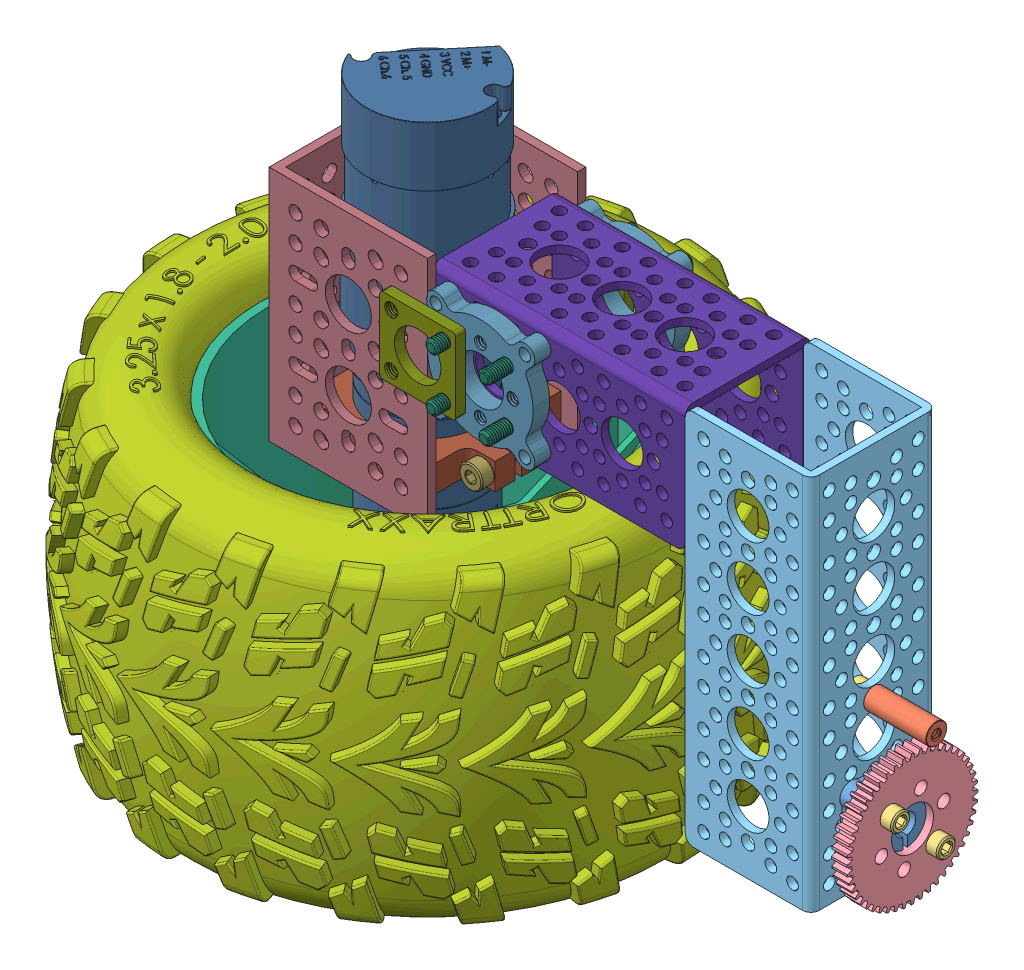
SolidWorks assembly Corner Wheel Assembly, configuration Default. Lengths in mm.
Overall size (237.64 178.61 166.05).
40 component instances, 18 part files, 13 mates.
Components (placement in the parent):
- steering-fixture-top^Corner Wheel Assembly-1: steering-fixture-top^Corner Wheel Assembly [Default] at (135.25 0 0) size (57.26 119.56 48.62) (virtual)
  - 0.25 Face Tapped Clamping Hub-1: 0.25 Face Tapped Clamping Hub [Default] at (9.525 0 0) x (0 0 -1) z (0 1 0) size (20.57 9.63 26.29)
  - 6_32 standoff-1: 6_32 standoff [Default] at (0 28.575 0) x (0 -0.906043 -0.423186) z (0 -0.423186 0.906043) size (6.34 19.26 6.34)
  - 6-32_SHCS-1: 6-32_SHCS [6-32 SHCS X .375] at (7.239 -6.9148 6.9148) x (0 0.135656 -0.990756) z (-1 0 0) size (5.74 5.74 13.03)
  - 6-32_SHCS-2: 6-32_SHCS [6-32 SHCS X .375] at (7.239 6.9148 -6.9148) x (0 0.993277 -0.11576) z (-1 0 0) size (5.74 5.74 13.03)
  - 6-32_SHCS-3: 6-32_SHCS [6-32 SHCS X .375] at (2.2225 -6.9148 -6.9148) x (0 -0.906043 -0.423186) z (1 0 0) size (5.74 5.74 13.03)
  - 48 Tooth 32 Pitch Gear-1: 48 Tooth 32 Pitch Gear [Default] at (6.985 0 0) x (0 0.258819 -0.965926) z (0 -0.965926 -0.258819) size (39.7 4.76 39.7)
  - 6-32_SHCS-4: 6-32_SHCS [6-32 SHCS X .375] at (2.2225 6.9148 6.9148) x (0 -0.906043 -0.423186) z (1 0 0) size (5.74 5.74 13.03)
  - 6-32_SHCS-5: 6-32_SHCS [6-32 SHCS X .375] at (7.239 28.575 0) x (0 0.98997 -0.141276) z (-1 0 0) size (5.74 5.74 13.03)
  - 4.5 Aluminum channel-1: 4.5 Aluminum channel [Default] at (0 -19.05 19.05) x (0 0 -1) z (0 1 0) size (38.1 38.1 114.3)
- Wheel Assembly-2: Wheel Assembly [Middle Wheel] x (-1 0 0) z (0 1 0) size (166.47 166.05 178.61) (flexible)
  - Wheel-1: Wheel [Default] at (0 0 -5.7032) x (0 0 -1) z (1 0 0) size (106.88 166.05 166.47)
    - Wheel Rim-1: Wheel Rim [Default] at (-5.7009 0 0) size (78.74 101.6 101.6)
    - Wheel Tire-1: Wheel Tire [Default] at (-5.7009 -0.0005 -0.0001) size (106.88 166.05 166.47)
  - 6-32_SHCS-5: 6-32_SHCS [6-32 SHCS X 1.250] at (9.1943 3.3307 1.201) x (-1 0 0) z (0 0 -1) size (5.74 5.74 35.26)
  - 6-32_SHCS-6: 6-32_SHCS [6-32 SHCS X 1.250] at (-9.1943 -3.3307 1.201) x (-1 0 0) z (0 0 -1) size (5.74 5.74 35.26)
  - wheel shell-1: wheel shell [Default] at (0 0 156.0711) x (-0.903132 -0.429363 0) z (0.429363 -0.903132 0) size (165.1 2.54 165.1) (hidden)
  - servocity-hub-545619assembly-1: servocity-hub-545619assembly [Default] at (-0.9738 -41.3522 -6.7488) x (-0.423986 -0.905669 0) z (-0.905669 0.423986 0) size (20.57 9.62 26.29)
    - 545619-1: 545619 [Default] at (-37.8643 4.2066 16.6508) size (20.57 9.62 26.29)
    - 632110_90128A121-1: 632110_90128A121 [Default] at (-42.6268 10.2391 4.0778) x (0 0 1) z (-1 0 0) size (5.74 5.74 13.19)
  - gobilda-435rpm-planetary-gearmotor-1: gobilda-435rpm-planetary-gearmotor [Default] at (0 0 8.4534) x (0.969869 0.243628 0) z (0 0 -1) size (37.5 37.5 140.72)
  - gobilda-32mm-motor-clamp-1401-0043-0032-1: gobilda-32mm-motor-clamp-1401-0043-0032 [Default] at (4.4026 0.7931 48.32) x (0 -1 0) z (1 0 0) size (43.27 8.04 47.02)
    - 1401-0043-0032-1: 1401-0043-0032 [Default] at (0.7931 12.12 -4.4026) size (43.27 8 46.5)
    - 2800-0004-0014_90128A207-1: 2800-0004-0014_90128A207 [Default] at (7.7931 12.12 -28.4026) x (0 0.161804 -0.986823) z (1 0 0) size (7 7 18.17)
  - gobilda-2hole-channel-1120-0002-0072-1: gobilda-2hole-channel-1120-0002-0072 [Default] at (21.5 0 28.2) x (0 1 0) z (1 0 0) size (48 72 48)
  - gobilda-to-actobotics-bracket-1206-0016-0004-1: gobilda-to-actobotics-bracket-1206-0016-0004 [Default] at (-43.03 -57.84 59.0834) x (0 -1 0) z (0 0 1) size (12.17 33.02 33.02)
    - 1206-0016-0004-1: 1206-0016-0004 [Default] at (-38.84 3.03 17.1166) size (5.21 33.02 33.02)
    - 2800-0004-0008_90128A207-1: 2800-0004-0008_90128A207 [Default] at (-26.84 11.03 25.1166) x (0 0 -1) z (1 0 0) size (7 7 12.17)
    - 2800-0004-0008_90128A207-2: 2800-0004-0008_90128A207 [Default] at (-26.84 11.03 9.1166) x (0 -1 0) z (1 0 0) size (7 7 12.17)
    - 2800-0004-0008_90128A207-3: 2800-0004-0008_90128A207 [Default] at (-26.84 -4.97 9.1166) x (0 0 1) z (1 0 0) size (7 7 12.17)
    - 2800-0004-0008_90128A207-4: 2800-0004-0008_90128A207 [Default] at (-26.84 -4.97 25.1166) x (0 1 0) z (1 0 0) size (7 7 12.17)
  - gobilda-to-actobotics-bracket-1206-0016-0004-2: gobilda-to-actobotics-bracket-1206-0016-0004 [Default] at (-36.97 57.84 59.0834) x (0 1 0) z (0 0 1) size (12.17 33.02 33.02)
    - 1206-0016-0004-1: 1206-0016-0004 [Default] at (-38.84 3.03 17.1166) size (5.21 33.02 33.02)
    - 2800-0004-0008_90128A207-1: 2800-0004-0008_90128A207 [Default] at (-26.84 11.03 25.1166) x (0 0 -1) z (1 0 0) size (7 7 12.17)
    - 2800-0004-0008_90128A207-2: 2800-0004-0008_90128A207 [Default] at (-26.84 11.03 9.1166) x (0 -1 0) z (1 0 0) size (7 7 12.17)
    - 2800-0004-0008_90128A207-3: 2800-0004-0008_90128A207 [Default] at (-26.84 -4.97 9.1166) x (0 0 1) z (1 0 0) size (7 7 12.17)
    - 2800-0004-0008_90128A207-4: 2800-0004-0008_90128A207 [Default] at (-26.84 -4.97 25.1166) x (0 1 0) z (1 0 0) size (7 7 12.17)
  - gobilda-threaded-plate-2803.step-1: gobilda-threaded-plate-2803.step [Default] at (-24 24 76.2) size (23 3.01 23)
  - gobilda-threaded-plate-2803.step-2: gobilda-threaded-plate-2803.step [Default] at (-24 -24 76.2) x (-1 0 0) z (0 0 1) size (23 3.01 23)
- 3 Aluminum Channel-1: 3 Aluminum Channel [Default] at (20.95 95.25 -19) x (0 0 1) z (1 0 0) size (38.1 38.1 76.2)
Mates (geometry in assembly coordinates):
- Coincident65: coincident aligned: plane of Wheel Assembly-2 through (0 0 0) normal (0 1 0); plane of assembly through (0 0 0) normal (0 1 0)
- Coincident66: coincident anti-aligned: plane of Wheel Assembly-2 through (0 0 0) normal (-1 0 0); plane of assembly through (0 0 0) normal (1 0 0)
- Coincident67: coincident aligned: plane of Wheel Assembly-2 through (0 0 0) normal (0 0 1); plane of assembly through (0 0 0) normal (0 0 1)
- Coincident68: coincident aligned: plane of steering-fixture-top^Corner Wheel Assembly-1 through (135.25 0 0) normal (0 1 0); plane of assembly through (0 0 0) normal (0 1 0)
- Coincident69: coincident aligned: plane of steering-fixture-top^Corner Wheel Assembly-1 through (135.25 0 0) normal (0 0 1); plane of assembly through (0 0 0) normal (0 0 1)
- Coincident84: coincident: line of steering-fixture-top^Corner Wheel Assembly-1/4.5 Aluminum channel-1 through (97.15 -16.51 -16.764) axis (0 1 0); plane of 3 Aluminum Channel-1 through (97.15 95.25 -19) normal (1 0 0)
- Coincident106: coincident anti-aligned: plane of 3 Aluminum Channel-1 through (97.15 95.25 -19) normal (0 0 -1); plane of Wheel Assembly-2/gobilda-to-actobotics-bracket-1206-0016-0004-1/1206-0016-0004-1 through (40 76.2 -19) normal (0 0 1)
- Concentric21: concentric anti-aligned: circle of 3 Aluminum Channel-1; circle of Wheel Assembly-2/gobilda-to-actobotics-bracket-1206-0016-0004-1/1206-0016-0004-1
- Concentric22: concentric anti-aligned: circle of 3 Aluminum Channel-1; circle of Wheel Assembly-2/gobilda-to-actobotics-bracket-1206-0016-0004-1/1206-0016-0004-1
- Concentric23: concentric anti-aligned: cylinder of 3 Aluminum Channel-1 through (53.4704 62.7296 19.1) axis (0 0 1) radius 1.778; cylinder of Wheel Assembly-2/gobilda-to-actobotics-bracket-1206-0016-0004-2/1206-0016-0004-1 through (53.4704 62.7296 24) axis (0 0 -1) radius 1.778
- Concentric24: concentric anti-aligned: cylinder of 3 Aluminum Channel-1 through (53.4704 89.6704 19.1) axis (0 0 1) radius 1.778; cylinder of Wheel Assembly-2/gobilda-to-actobotics-bracket-1206-0016-0004-2/1206-0016-0004-1 through (53.4704 89.6704 24) axis (0 0 -1) radius 1.778
- Coincident107: coincident anti-aligned: plane of steering-fixture-top^Corner Wheel Assembly-1/4.5 Aluminum channel-1 through (97.15 95.25 -16.764) normal (-1 0 0); plane of 3 Aluminum Channel-1 through (97.15 95.25 -19) normal (1 0 0)
- Coincident108: coincident aligned: plane of steering-fixture-top^Corner Wheel Assembly-1/4.5 Aluminum channel-1 through (135.25 95.25 19.05) normal (0 1 0); plane of 3 Aluminum Channel-1 through (97.15 95.25 19.1) normal (0 1 0)
